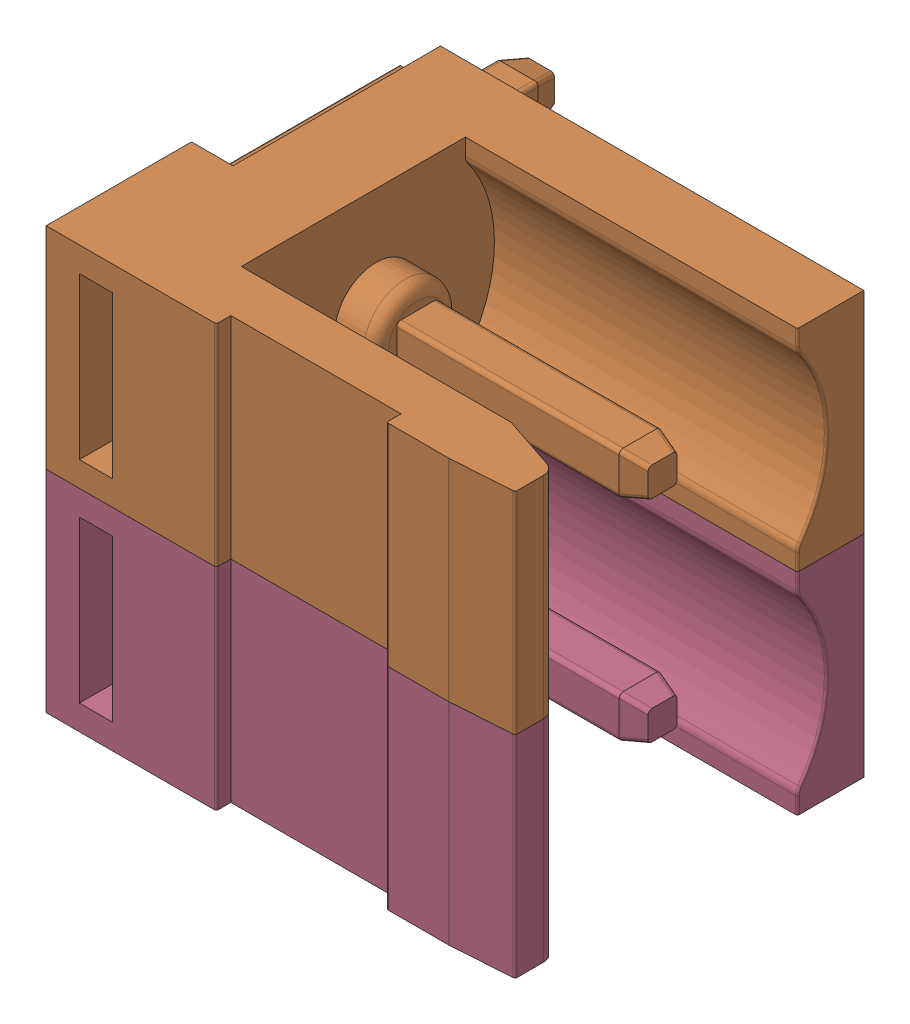
SolidWorks assembly P2, configuration 默认. Lengths in mm.
Overall size (11.3 10.16 11.5).
6 component instances, 2 part files, 0 mates.
Components (placement in the parent):
- KF2EDGK-1P_H-1: KF2EDGK-1P_H [默认] at (94.488 56.388 0) x (0 1 0) z (0 0 1) size (5.08 11.3 11.5)
  - LOGO横_-_0.5MM-1: LOGO横_-_0.5MM [默认] at (0.513 -1.4708 0) x (-1 0 0) z (0 0 -1) size (1.35 0.5 0.02)
  - KF2EDGK-1P_H-1: KF2EDGK-1P_H [默认] at origin size (5.08 11.3 11.5)
- KF2EDGK-1P_H-2: KF2EDGK-1P_H [默认] at (94.4881 51.3079 0) x (0 1 0) z (0 0 1) size (5.08 11.3 11.5)
  - LOGO横_-_0.5MM-1: LOGO横_-_0.5MM [默认] at (0.513 -1.4708 0) x (-1 0 0) z (0 0 -1) size (1.35 0.5 0.02)
  - KF2EDGK-1P_H-1: KF2EDGK-1P_H [默认] at origin size (5.08 11.3 11.5)
